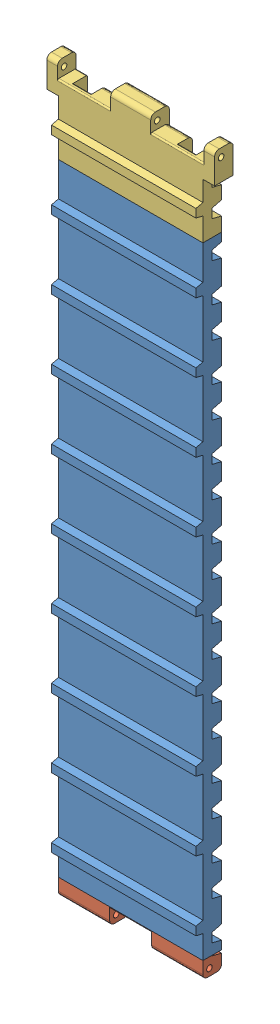
SolidWorks assembly Assem2, configuration Default. Lengths in mm.
Overall size (36 273.62 5.5).
3 component instances, 3 part files, 5 mates.
Components (placement in the parent):
- гусеница 2.0-1: гусеница 2.0 [Default] at (-104.7713 -106.7492 267.25) size (31 270 5.5)
- гусеница крипеж_1-1: гусеница крипеж_1 [Default] at (-104.7713 -95.5492 267.25) x (-1 0 0) z (0 0 1) size (31 3.62 4)
- гусеница крипеж_2-1: гусеница крипеж_2 [Default] at (-104.7713 26.6308 267.25) size (36 18.22 5.5)
Mates (geometry in assembly coordinates):
- Coincident1: coincident: plane of гусеница 2.0-1 through (-121.7713 26.6308 271.25) normal (0 1 0); plane of гусеница крипеж_2-1 through (-121.7713 26.6308 271.25) normal (0 -1 0)
- Coincident2: coincident: point of гусеница 2.0-1; point of гусеница крипеж_2-1
- Coincident3: coincident: plane of гусеница 2.0-1 through (-121.7713 -106.7492 271.25) normal (0 -1 0); plane of гусеница крипеж_1-1 through (-129.3717 -106.7492 256.9964) normal (0 1 0)
- Coincident4: coincident: point of гусеница 2.0-1; point of гусеница крипеж_1-1
- Coincident5: coincident: point of гусеница 2.0-1; point of гусеница крипеж_1-1
